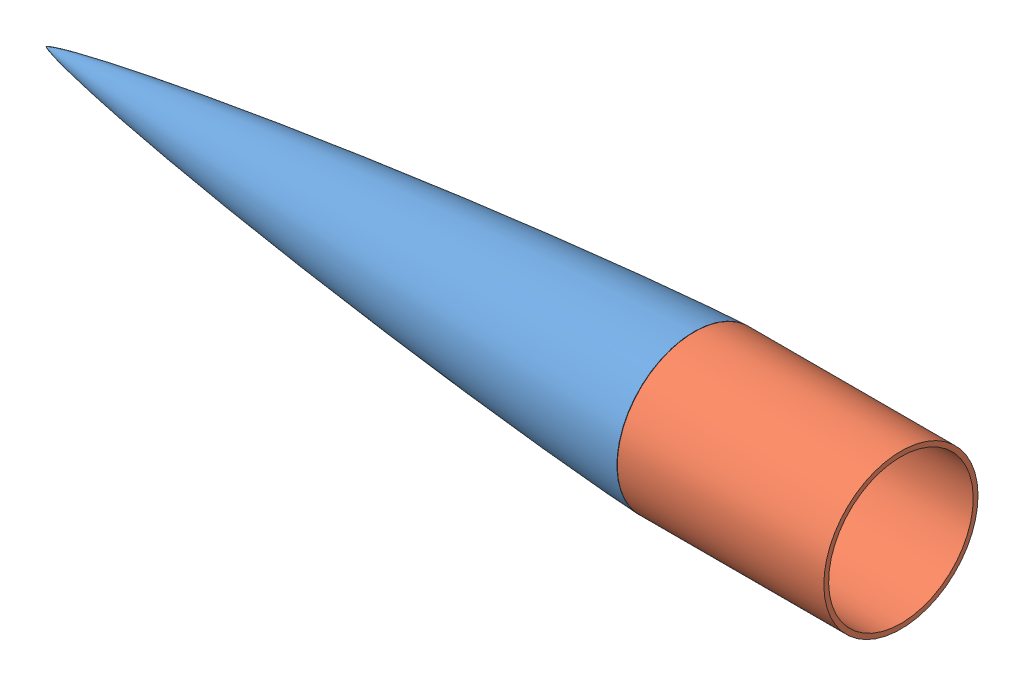
SolidWorks assembly Assem1, configuration Default. Lengths in mm.
Overall size (262.81 58.12 58.12).
2 component instances, 2 part files, 1 mates.
Components (placement in the parent):
- VonKarmanNoseCone-1: VonKarmanNoseCone [Default] at (-66.2945 121.2561 162.8725) size (199.26 47.4 47.4)
- BodyTube-1: BodyTube [Default] at (133.0153 121.2561 162.8725) x (0 -0.260789 -0.965396) z (1 0 0) size (47.4 47.4 63.5)
Mates (geometry in assembly coordinates):
- Concentric1: concentric anti-aligned: circle of VonKarmanNoseCone-1; circle of BodyTube-1
